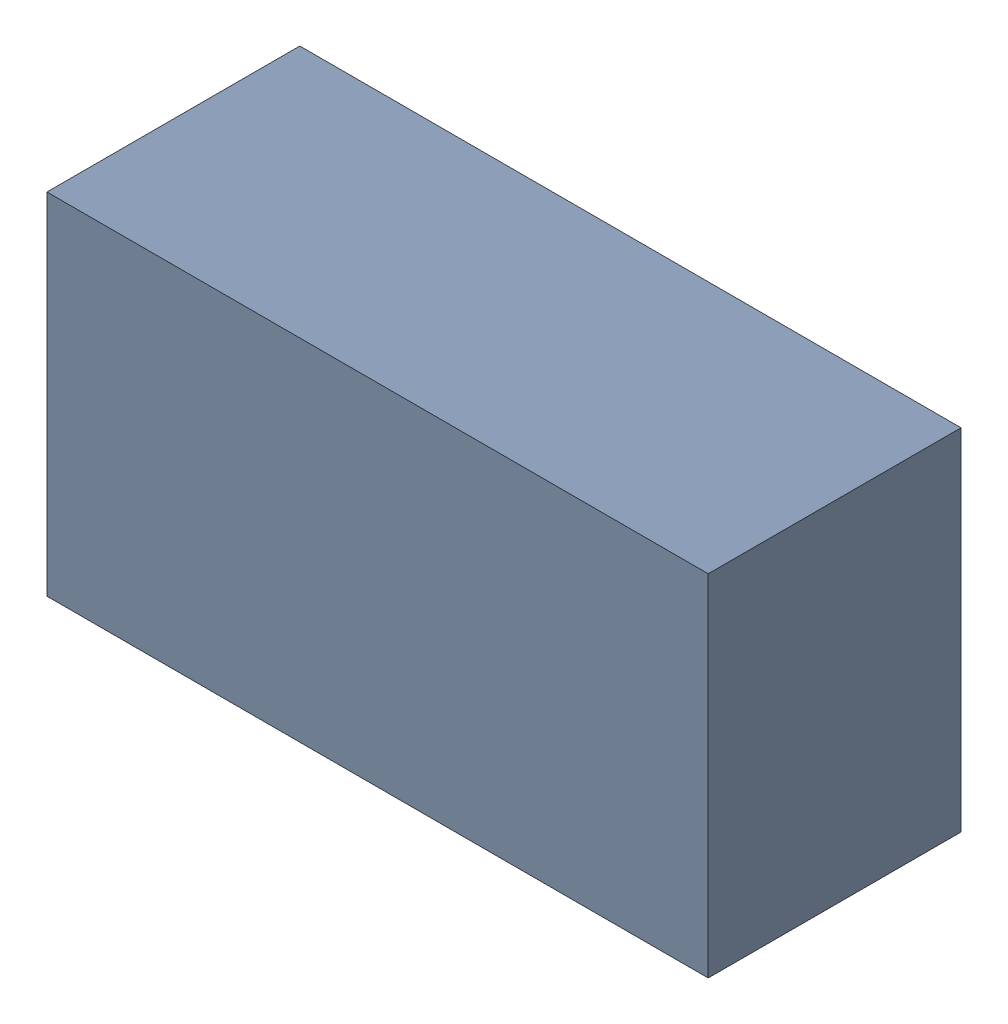
SolidWorks assembly C6, configuration Default. Lengths in mm.
Overall size (3.4 1.8 1.3).
2 component instances, 1 part files, 0 mates.
Components (placement in the parent):
- 580487568-1: 580487568 [Default] at (230.759 111.76 0) size (3.4 1.8 1.3)
  - Extruded_5-1: Extruded_5 [Default] at origin size (3.4 1.8 1.3)
